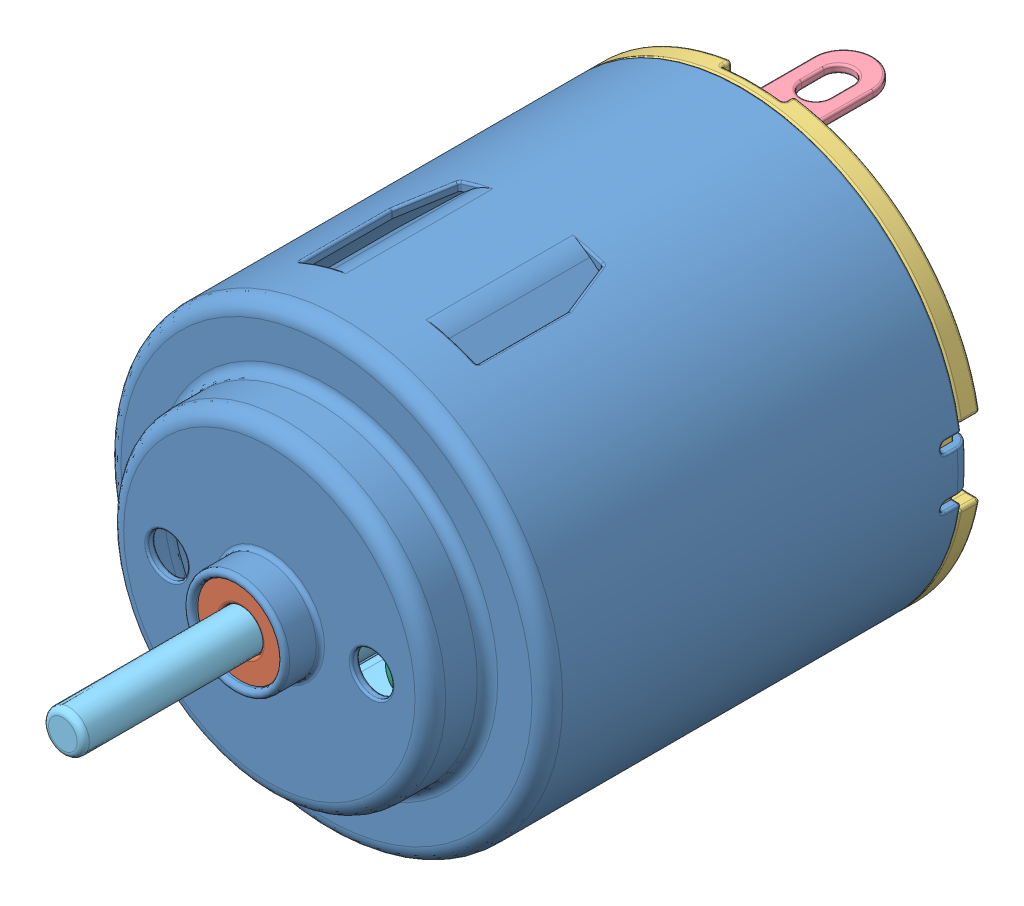
SolidWorks assembly ELENCO DC Motor 3V, configuration Predeterminado. Lengths in mm.
Overall size (22.78 22.72 39.63).
9 component instances, 6 part files, 19 mates.
Components (placement in the parent):
- ELENCO MOTOR HOUSING 01-1: ELENCO MOTOR HOUSING 01 [Predeterminado] at (0 0 24.0663) size (21.61 21.6 25.37)
- ELENCO FRONT BUSHING-1: ELENCO FRONT BUSHING [Predeterminado] at (0 0 28.0103) x (0.939098 -0.34365 0) z (0 0 1) size (4.5 4.5 0.5)
- ELENCO MOTOR BACK 01-1: ELENCO MOTOR BACK 01 [Predeterminado] at (0 0 4.731) x (-1 0 0) z (0 0 -1) size (21.23 21.59 3.58)
- Terminal3V-1: Terminal3V [Predeterminado] at (0 -8.7 5.331) x (1 0 0) z (0 1 0) size (2.9 8 0.4)
- Terminal3V-2: Terminal3V [Predeterminado] at (0 8.7 5.331) x (1 0 0) z (0 1 0) size (2.9 8 0.4)
- ELENCO ARMATURE 01-1: ELENCO ARMATURE 01 [Predeterminado] at (0 0 36.9603) x (-0.892263 0.451515 0) z (0 0 1) size (17 16.86 36.46)
- Enrolamento3V-1: Enrolamento3V [Predeterminado] at (2.0691 4.0889 14.4603) x (0.892263 -0.451515 0) z (0 0 1) size (7 3 16)
- Enrolamento3V-2: Enrolamento3V [Predeterminado] at (-4.5756 -0.2525 14.4603) x (-0.055108 0.99848 0) z (0 0 1) size (7 3 16)
- Enrolamento3V-3: Enrolamento3V [Predeterminado] at (2.5065 -3.8363 14.4603) x (-0.837155 -0.546965 0) z (0 0 1) size (7 3 16)
Mates (geometry in assembly coordinates):
- Concentric1: concentric aligned: cylinder of ELENCO MOTOR HOUSING 01-1 through (0 0 3.731) axis (0 0 1) radius 10.8; cylinder of ELENCO ARMATURE 01-1 through (0 0 0.5003) axis (0 0 1) radius 1
- Coincident1: coincident anti-aligned: plane of ELENCO ARMATURE 01-1 through (0 0 26.4603) normal (0 0 1); plane of ELENCO MOTOR HOUSING 01-1 through (0 0 26.4603) normal (0 0 -1)
- Concentric2: concentric anti-aligned: cylinder of ELENCO MOTOR HOUSING 01-1 through (0 0 3.731) axis (0 0 1) radius 10.8; cylinder of ELENCO FRONT BUSHING-1 through (0 0 28.2603) axis (0 0 -1) radius 1
- Distance1: distance = 1.3 mm aligned: plane of ELENCO MOTOR HOUSING 01-1 through (0 0 26.4603) normal (0 0 -1); plane of ELENCO FRONT BUSHING-1 through (0 0 27.7603) normal (0 0 -1)
- Concentric3: concentric aligned: cylinder of ELENCO MOTOR HOUSING 01-1 through (0 0 3.731) axis (0 0 1) radius 10.8; cylinder of ELENCO MOTOR BACK 01-1 through (0 0 2.731) axis (0 0 1) radius 10.795
- Coincident2: coincident anti-aligned: plane of ELENCO MOTOR HOUSING 01-1 through (0 0 3.731) normal (0 0 -1); plane of ELENCO MOTOR BACK 01-1 through (0 10.795 3.731) normal (0 0 1)
- Coincident3: coincident aligned: plane of ELENCO MOTOR HOUSING 01-1 through (0 0 24.0663) normal (0 1 0); plane of ELENCO MOTOR BACK 01-1
- Coincident4: coincident aligned: plane of Terminal3V-1 through (-1.45 -8.5 5.331) normal (0 0 1); plane of Terminal3V-2 through (-1.45 8.9 5.331) normal (0 0 1)
- Coincident5: coincident aligned: plane of Terminal3V-1; plane of Terminal3V-2
- Coincident6: coincident aligned: plane of ELENCO MOTOR HOUSING 01-1 through (0 0 24.0663) normal (1 0 0); plane of Terminal3V-1
- Parallel1: parallel aligned: plane of ELENCO MOTOR HOUSING 01-1 through (0 0 24.0663) normal (0 1 0); plane of Terminal3V-1 through (0 -8.7 5.331) normal (0 1 0)
- Coincident10: coincident anti-aligned: plane of Terminal3V-2 through (-1.45 8.9 5.331) normal (0 1 0); plane of ELENCO MOTOR BACK 01-1 through (1.5 8.9 4.731) normal (0 -1 0)
- Coincident11: coincident anti-aligned: plane of Terminal3V-1 through (-1.45 -8.9 5.331) normal (0 -1 0); plane of ELENCO MOTOR BACK 01-1 through (1.5 -8.9 4.731) normal (0 1 0)
- Coincident12: coincident: plane of ELENCO MOTOR HOUSING 01-1 through (0 0 24.0663) normal (1 0 0); plane of assembly through (0 0 0) normal (1 0 0)
- Coincident13: coincident: plane of ELENCO MOTOR HOUSING 01-1 through (0 0 24.0663) normal (0 1 0); plane of assembly through (0 0 0) normal (0 1 0)
- Distance2: distance = 2.5 mm anti-aligned: plane of ELENCO MOTOR BACK 01-1 through (0 0 2.731) normal (0 0 -1); cylinder of Terminal3V-1 through (0 -8.9 -1.219) axis (0 -1 0) radius 1.45
- Coincident14: coincident anti-aligned: plane of ELENCO ARMATURE 01-1 through (2.0076 6.1822 0.5003) normal (-0.892263 0.451515 0); plane of Enrolamento3V-1 through (1.8541 5.8788 9.9603) normal (0.892263 -0.451515 0)
- Coincident15: coincident anti-aligned: plane of ELENCO ARMATURE 01-1 through (0 0 18.9603) normal (0 0 1); plane of Enrolamento3V-1 through (1.8541 5.8788 18.9603) normal (0 0 -1)
- Tangent1: tangent aligned: cylinder of ELENCO ARMATURE 01-1 through (0 0 0.5003) axis (0 0 1) radius 6.5; cylinder of Enrolamento3V-1 through (3.8536 3.1858 9.9603) axis (0 0 1) radius 1.5
